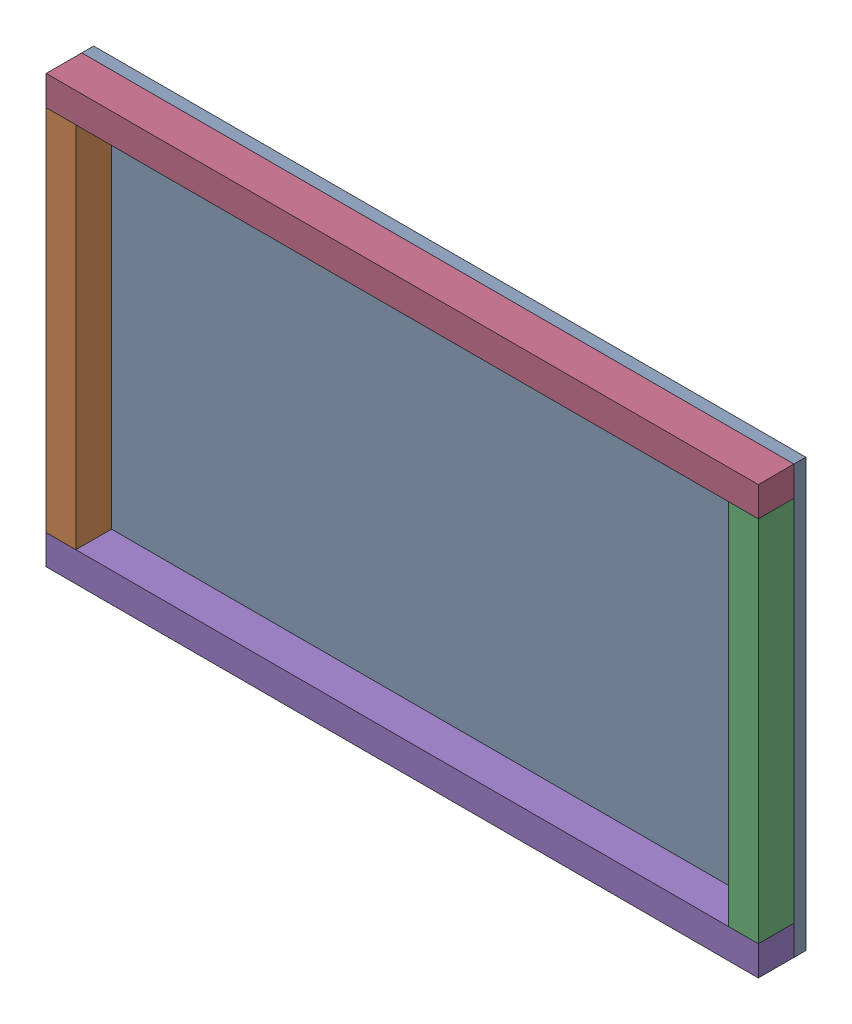
SolidWorks assembly БокСб, configuration По умолчанию. Lengths in mm.
Overall size (600 360 40).
5 component instances, 3 part files, 13 mates.
Components (placement in the parent):
- ПластикБ-1: ПластикБ [По умолчанию] at (-0.0082 1.2046 0) x (1 0 0) z (0 -1 0) size (600 10 360)
- Брус360-1: Брус360 [По умолчанию] at (-287.5082 -153.7954 25) x (0 1 0) z (0 0 1) size (310 25 30)
- Брус360-2: Брус360 [По умолчанию] at (287.4918 -153.7954 25) x (0 1 0) z (0 0 -1) size (310 25 30)
- Брус560-1: Брус560 [По умолчанию] at (-300.0082 168.7046 25) size (600 25 30)
- Брус560-2: Брус560 [По умолчанию] at (-300.0082 -166.2954 25) size (600 25 30)
Mates (geometry in assembly coordinates):
- Совпадение2: coincident anti-aligned: plane of ПластикБ-1 through (-0.0082 1.2046 0) normal (0 0 -1)
- Совпадение4: coincident aligned: plane of ПластикБ-1 through (-300.0082 181.2046 10) normal (-1 0 0); plane of Брус360-1 through (-300.0082 156.2046 40) normal (-1 0 0)
- Совпадение5: coincident anti-aligned: plane of ПластикБ-1 through (-0.0082 1.2046 10) normal (0 0 1); plane of Брус360-1 through (-275.0082 156.2046 10) normal (0 0 -1)
- Расстояние1: distance = 25 mm aligned: plane of ПластикБ-1 through (-300.0082 181.2046 10) normal (0 1 0); plane of Брус360-1 through (-287.5082 156.2046 25) normal (0 1 0)
- Совпадение8: coincident aligned: plane of Брус360-1 through (-275.0082 156.2046 40) normal (0 0 1); plane of Брус360-2 through (274.9918 156.2046 40) normal (0 0 1)
- Совпадение9: coincident aligned: plane of ПластикБ-1 through (299.9918 181.2046 10) normal (1 0 0); plane of Брус360-2 through (299.9918 156.2046 10) normal (1 0 0)
- Совпадение10: coincident aligned: plane of Брус360-1 through (-287.5082 156.2046 25) normal (0 1 0); plane of Брус360-2 through (287.4918 156.2046 25) normal (0 1 0)
- Совпадение11: coincident aligned: plane of ПластикБ-1 through (-300.0082 181.2046 10) normal (0 1 0); plane of Брус560-1 through (299.9918 181.2046 40) normal (0 1 0)
- Совпадение12: coincident aligned: plane of Брус360-1 through (-275.0082 156.2046 40) normal (0 0 1); plane of Брус560-1 through (299.9918 156.2046 40) normal (0 0 1)
- Совпадение13: coincident aligned: plane of Брус360-2 through (299.9918 156.2046 10) normal (1 0 0); plane of Брус560-1 through (299.9918 168.7046 25) normal (1 0 0)
- Совпадение15: coincident aligned: plane of Брус560-1 through (299.9918 156.2046 40) normal (0 0 1); plane of Брус560-2 through (299.9918 -178.7954 40) normal (0 0 1)
- Совпадение16: coincident aligned: plane of Брус560-1 through (299.9918 168.7046 25) normal (1 0 0); plane of Брус560-2 through (299.9918 -166.2954 25) normal (1 0 0)
- Совпадение17: coincident aligned: plane of ПластикБ-1 through (-300.0082 -178.7954 10) normal (0 -1 0); plane of Брус560-2 through (299.9918 -178.7954 40) normal (0 -1 0)
